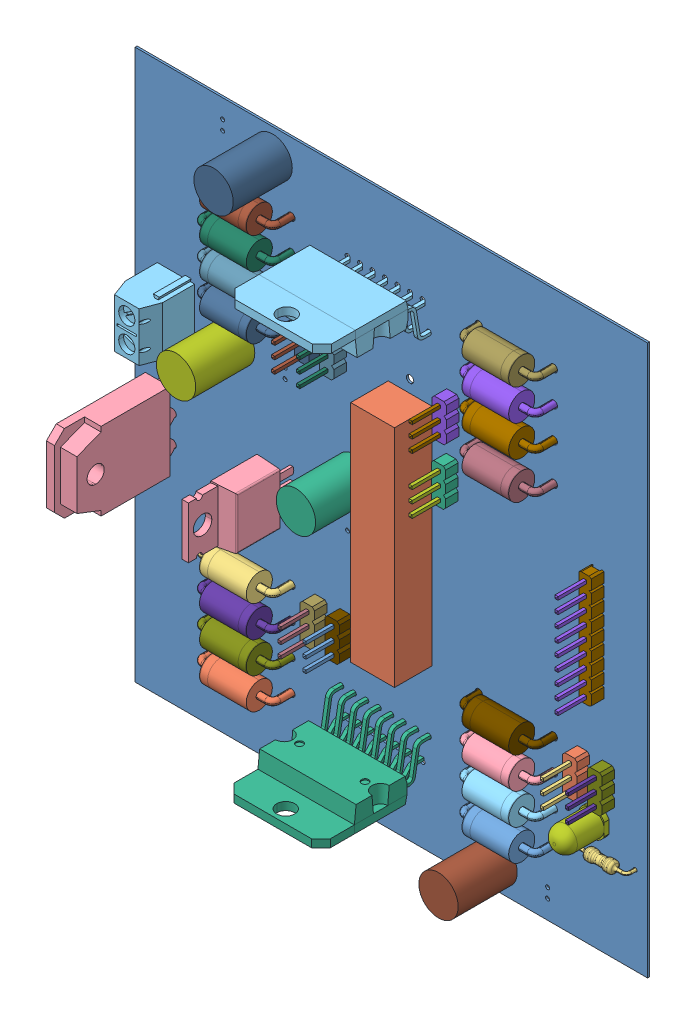
SolidWorks assembly TestServoCircuit, configuration Default. Lengths in mm.
Overall size (104.14 111.76 40.3).
108 component instances, 47 part files, 0 mates.
Components (placement in the parent):
- TestServoCircuit(2)^TestServoCircuit-1: TestServoCircuit(2)^TestServoCircuit [Default] at origin size (104.14 111.76 40.3) (virtual)
  - Board^TestServoCircuit(2)_TestServoCircuit-1: Board^TestServoCircuit(2)_TestServoCircuit [Default] at origin size (104.14 111.76 0.41) (virtual)
    - Open CASCADE STEP translator 6.8 2.1.1^Board_TestServoCircuit(2)_TestServoCircuit-1: Open CASCADE STEP translator 6.8 2.1.1^Board_TestServoCircuit(2)_TestServoCircuit [Default] at (0 0 -0.4115) size (104.14 111.76 0.41) (virtual)
  - R2^TestServoCircuit(2)_TestServoCircuit-1: R2^TestServoCircuit(2)_TestServoCircuit [Default] at origin size (8.89 45.72 7.62) (virtual)
    - 8621058528^R2_TestServoCircuit(2)_TestServoCircuit-1: 8621058528^R2_TestServoCircuit(2)_TestServoCircuit [Default] at (55.88 55.88 0) size (8.89 45.72 7.62) (virtual)
      - Extruded^8621058528_R2_TestServoCircuit(2)_TestServoCircuit-1: Extruded^8621058528_R2_TestServoCircuit(2)_TestServoCircuit [Default] at origin size (8.89 45.72 7.62) (virtual)
  - R1^TestServoCircuit(2)_TestServoCircuit-1: R1^TestServoCircuit(2)_TestServoCircuit [Default] at origin size (10.77 2.31 5.47) (virtual)
    - SW3dPS-RESISTOR,_0.25_W,_0.4_IN_LEAD_PITCH^R1_TestServoCircuit(2)_TestServoCircuit-1: SW3dPS-RESISTOR,_0.25_W,_0.4_IN_LEAD_PITCH^R1_TestServoCircuit(2)_TestServoCircuit [Default] at (101.5999 17.7799 0) x (-1 0 0) z (0 1 0) size (10.77 5.47 2.31) (virtual)
  - Q1^TestServoCircuit(2)_TestServoCircuit-1: Q1^TestServoCircuit(2)_TestServoCircuit [Default] at origin size (5 15.8 40.3) (virtual)
    - TO-3P^Q1_TestServoCircuit(2)_TestServoCircuit-1: TO-3P^Q1_TestServoCircuit(2)_TestServoCircuit [Default] at (5.5881 51.1699 13.563) x (0 1 0) z (1 0 0) size (15.8 40.3 5) (virtual)
  - P1^TestServoCircuit(2)_TestServoCircuit-1: P1^TestServoCircuit(2)_TestServoCircuit [Default] at origin size (7.6 10.6 13) (virtual)
    - User_Library-Terminal-Screw-3A-2way^P1_TestServoCircuit(2)_TestServoCircuit-1: User_Library-Terminal-Screw-3A-2way^P1_TestServoCircuit(2)_TestServoCircuit [Default] at (8.3199 71.1201 0.0127) x (0 -1 0) z (-1 0 0) size (10.6 13 7.6) (virtual)
  - J8^TestServoCircuit(2)_TestServoCircuit-1: J8^TestServoCircuit(2)_TestServoCircuit [Default] at origin size (2.92 7.62 12.19) (virtual)
    - User_Library-PinHeaderX3^J8_TestServoCircuit(2)_TestServoCircuit-1: User_Library-PinHeaderX3^J8_TestServoCircuit(2)_TestServoCircuit [Default] at (64.707 71.12 0.508) x (0 -1 0) z (-1 0 0) size (7.62 12.19 2.92) (virtual)
      - User_Library-PinHeaderX3_PinHeader_Body_1^User_Library-PinHeaderX3_J8_TestServoCircuit(2)_TestServoCircuit-1: User_Library-PinHeaderX3_PinHeader_Body_1^User_Library-PinHeaderX3_J8_TestServoCircuit(2)_TestServoCircuit [Default] at origin size (7.62 2.54 2.92) (virtual)
      - User_Library-PinHeaderX3_PinHeader_Pins_1^User_Library-PinHeaderX3_J8_TestServoCircuit(2)_TestServoCircuit-1: User_Library-PinHeaderX3_PinHeader_Pins_1^User_Library-PinHeaderX3_J8_TestServoCircuit(2)_TestServoCircuit [Default] at origin size (5.72 12.19 0.64) (virtual)
  - J7^TestServoCircuit(2)_TestServoCircuit-1: J7^TestServoCircuit(2)_TestServoCircuit [Default] at origin size (2.92 7.62 12.19) (virtual)
    - User_Library-PinHeaderX3^J7_TestServoCircuit(2)_TestServoCircuit-1: User_Library-PinHeaderX3^J7_TestServoCircuit(2)_TestServoCircuit [Default] at (64.833 77.47 0.508) x (0 1 0) z (1 0 0) size (7.62 12.19 2.92) (virtual)
      - User_Library-PinHeaderX3_PinHeader_Body_1^User_Library-PinHeaderX3_J7_TestServoCircuit(2)_TestServoCircuit-1: User_Library-PinHeaderX3_PinHeader_Body_1^User_Library-PinHeaderX3_J7_TestServoCircuit(2)_TestServoCircuit [Default] at origin size (7.62 2.54 2.92) (virtual)
      - User_Library-PinHeaderX3_PinHeader_Pins_1^User_Library-PinHeaderX3_J7_TestServoCircuit(2)_TestServoCircuit-1: User_Library-PinHeaderX3_PinHeader_Pins_1^User_Library-PinHeaderX3_J7_TestServoCircuit(2)_TestServoCircuit [Default] at origin size (5.72 12.19 0.64) (virtual)
  - J6^TestServoCircuit(2)_TestServoCircuit-1: J6^TestServoCircuit(2)_TestServoCircuit [Default] at origin size (2.92 7.62 12.19) (virtual)
    - User_Library-PinHeaderX3^J6_TestServoCircuit(2)_TestServoCircuit-1: User_Library-PinHeaderX3^J6_TestServoCircuit(2)_TestServoCircuit [Default] at (36.893 77.4446 0.508) x (0 1 0) z (1 0 0) size (7.62 12.19 2.92) (virtual)
      - User_Library-PinHeaderX3_PinHeader_Body_1^User_Library-PinHeaderX3_J6_TestServoCircuit(2)_TestServoCircuit-1: User_Library-PinHeaderX3_PinHeader_Body_1^User_Library-PinHeaderX3_J6_TestServoCircuit(2)_TestServoCircuit [Default] at origin size (7.62 2.54 2.92) (virtual)
      - User_Library-PinHeaderX3_PinHeader_Pins_1^User_Library-PinHeaderX3_J6_TestServoCircuit(2)_TestServoCircuit-1: User_Library-PinHeaderX3_PinHeader_Pins_1^User_Library-PinHeaderX3_J6_TestServoCircuit(2)_TestServoCircuit [Default] at origin size (5.72 12.19 0.64) (virtual)
  - J5^TestServoCircuit(2)_TestServoCircuit-1: J5^TestServoCircuit(2)_TestServoCircuit [Default] at origin size (2.92 7.62 12.19) (virtual)
    - User_Library-PinHeaderX3^J5_TestServoCircuit(2)_TestServoCircuit-1: User_Library-PinHeaderX3^J5_TestServoCircuit(2)_TestServoCircuit [Default] at (38.037 33.02 0.508) x (0 -1 0) z (-1 0 0) size (7.62 12.19 2.92) (virtual)
      - User_Library-PinHeaderX3_PinHeader_Body_1^User_Library-PinHeaderX3_J5_TestServoCircuit(2)_TestServoCircuit-1: User_Library-PinHeaderX3_PinHeader_Body_1^User_Library-PinHeaderX3_J5_TestServoCircuit(2)_TestServoCircuit [Default] at origin size (7.62 2.54 2.92) (virtual)
      - User_Library-PinHeaderX3_PinHeader_Pins_1^User_Library-PinHeaderX3_J5_TestServoCircuit(2)_TestServoCircuit-1: User_Library-PinHeaderX3_PinHeader_Pins_1^User_Library-PinHeaderX3_J5_TestServoCircuit(2)_TestServoCircuit [Default] at origin size (5.72 12.19 0.64) (virtual)
  - J4^TestServoCircuit(2)_TestServoCircuit-1: J4^TestServoCircuit(2)_TestServoCircuit [Default] at origin size (2.92 7.62 12.19) (virtual)
    - User_Library-PinHeaderX3^J4_TestServoCircuit(2)_TestServoCircuit-1: User_Library-PinHeaderX3^J4_TestServoCircuit(2)_TestServoCircuit [Default] at (41.973 77.4446 0.508) x (0 1 0) z (1 0 0) size (7.62 12.19 2.92) (virtual)
      - User_Library-PinHeaderX3_PinHeader_Body_1^User_Library-PinHeaderX3_J4_TestServoCircuit(2)_TestServoCircuit-1: User_Library-PinHeaderX3_PinHeader_Body_1^User_Library-PinHeaderX3_J4_TestServoCircuit(2)_TestServoCircuit [Default] at origin size (7.62 2.54 2.92) (virtual)
      - User_Library-PinHeaderX3_PinHeader_Pins_1^User_Library-PinHeaderX3_J4_TestServoCircuit(2)_TestServoCircuit-1: User_Library-PinHeaderX3_PinHeader_Pins_1^User_Library-PinHeaderX3_J4_TestServoCircuit(2)_TestServoCircuit [Default] at origin size (5.72 12.19 0.64) (virtual)
  - J3^TestServoCircuit(2)_TestServoCircuit-1: J3^TestServoCircuit(2)_TestServoCircuit [Default] at origin size (2.92 7.62 12.19) (virtual)
    - User_Library-PinHeaderX3^J3_TestServoCircuit(2)_TestServoCircuit-1: User_Library-PinHeaderX3^J3_TestServoCircuit(2)_TestServoCircuit [Default] at (96.457 33.02 0.508) x (0 -1 0) z (-1 0 0) size (7.62 12.19 2.92) (virtual)
      - User_Library-PinHeaderX3_PinHeader_Body_1^User_Library-PinHeaderX3_J3_TestServoCircuit(2)_TestServoCircuit-1: User_Library-PinHeaderX3_PinHeader_Body_1^User_Library-PinHeaderX3_J3_TestServoCircuit(2)_TestServoCircuit [Default] at origin size (7.62 2.54 2.92) (virtual)
      - User_Library-PinHeaderX3_PinHeader_Pins_1^User_Library-PinHeaderX3_J3_TestServoCircuit(2)_TestServoCircuit-1: User_Library-PinHeaderX3_PinHeader_Pins_1^User_Library-PinHeaderX3_J3_TestServoCircuit(2)_TestServoCircuit [Default] at origin size (5.72 12.19 0.64) (virtual)
  - J2^TestServoCircuit(2)_TestServoCircuit-1: J2^TestServoCircuit(2)_TestServoCircuit [Default] at origin size (2.92 7.62 12.19) (virtual)
    - User_Library-PinHeaderX3^J2_TestServoCircuit(2)_TestServoCircuit-1: User_Library-PinHeaderX3^J2_TestServoCircuit(2)_TestServoCircuit [Default] at (43.117 33.02 0.508) x (0 -1 0) z (-1 0 0) size (7.62 12.19 2.92) (virtual)
      - User_Library-PinHeaderX3_PinHeader_Body_1^User_Library-PinHeaderX3_J2_TestServoCircuit(2)_TestServoCircuit-1: User_Library-PinHeaderX3_PinHeader_Body_1^User_Library-PinHeaderX3_J2_TestServoCircuit(2)_TestServoCircuit [Default] at origin size (7.62 2.54 2.92) (virtual)
      - User_Library-PinHeaderX3_PinHeader_Pins_1^User_Library-PinHeaderX3_J2_TestServoCircuit(2)_TestServoCircuit-1: User_Library-PinHeaderX3_PinHeader_Pins_1^User_Library-PinHeaderX3_J2_TestServoCircuit(2)_TestServoCircuit [Default] at origin size (5.72 12.19 0.64) (virtual)
  - J1^TestServoCircuit(2)_TestServoCircuit-1: J1^TestServoCircuit(2)_TestServoCircuit [Default] at origin size (2.92 7.62 12.19) (virtual)
    - User_Library-PinHeaderX3^J1_TestServoCircuit(2)_TestServoCircuit-1: User_Library-PinHeaderX3^J1_TestServoCircuit(2)_TestServoCircuit [Default] at (91.377 33.02 0.508) x (0 -1 0) z (-1 0 0) size (7.62 12.19 2.92) (virtual)
      - User_Library-PinHeaderX3_PinHeader_Body_1^User_Library-PinHeaderX3_J1_TestServoCircuit(2)_TestServoCircuit-1: User_Library-PinHeaderX3_PinHeader_Body_1^User_Library-PinHeaderX3_J1_TestServoCircuit(2)_TestServoCircuit [Default] at origin size (7.62 2.54 2.92) (virtual)
      - User_Library-PinHeaderX3_PinHeader_Pins_1^User_Library-PinHeaderX3_J1_TestServoCircuit(2)_TestServoCircuit-1: User_Library-PinHeaderX3_PinHeader_Pins_1^User_Library-PinHeaderX3_J1_TestServoCircuit(2)_TestServoCircuit [Default] at origin size (5.72 12.19 0.64) (virtual)
  - IC3^TestServoCircuit(2)_TestServoCircuit-1: IC3^TestServoCircuit(2)_TestServoCircuit [Default] at origin size (4.69 11.21 29.33) (virtual)
    - SW3dPS-TO220AB^IC3_TestServoCircuit(2)_TestServoCircuit-1: SW3dPS-TO220AB^IC3_TestServoCircuit(2)_TestServoCircuit [Default] at (31.8806 48.304 -10.16) x (0 1 0) z (0 0 1) size (11.21 4.69 29.33) (virtual)
  - IC2^TestServoCircuit(2)_TestServoCircuit-1: IC2^TestServoCircuit(2)_TestServoCircuit [Default] at origin size (19.6 9.07 24.92) (virtual)
    - User_Library-MULTIWAT_T15^IC2_TestServoCircuit(2)_TestServoCircuit-1: User_Library-MULTIWAT_T15^IC2_TestServoCircuit(2)_TestServoCircuit [Default] at (41.1018 100.2586 5.2392) x (0 -1 0) z (-1 0 0) size (9.07 24.92 19.6) (virtual)
  - IC1^TestServoCircuit(2)_TestServoCircuit-1: IC1^TestServoCircuit(2)_TestServoCircuit [Default] at origin size (19.6 9.07 24.92) (virtual)
    - User_Library-MULTIWAT_T15^IC1_TestServoCircuit(2)_TestServoCircuit-1: User_Library-MULTIWAT_T15^IC1_TestServoCircuit(2)_TestServoCircuit [Default] at (60.4983 11.5014 5.2392) x (0 1 0) z (1 0 0) size (9.07 24.92 19.6) (virtual)
  - D17^TestServoCircuit(2)_TestServoCircuit-1: D17^TestServoCircuit(2)_TestServoCircuit [Default] at origin size (5.3 5.6 14.3) (virtual)
    - LED_5mm_Green^D17_TestServoCircuit(2)_TestServoCircuit-1: LED_5mm_Green^D17_TestServoCircuit(2)_TestServoCircuit [Default] at (93.9801 22.8601 -3.5) x (1 0 0) z (0 -1 0) size (5.3 14.3 5.6) (virtual)
  - D16^TestServoCircuit(2)_TestServoCircuit-1: D16^TestServoCircuit(2)_TestServoCircuit [Default] at origin size (16.3 5.3 8.65) (virtual)
    - User_Library-BYW98^D16_TestServoCircuit(2)_TestServoCircuit-1: User_Library-BYW98^D16_TestServoCircuit(2)_TestServoCircuit [Default] at (77.47 91.4399 3.65) x (-1 0 0) z (0 1 0) size (16.3 8.65 5.3) (virtual)
  - D15^TestServoCircuit(2)_TestServoCircuit-1: D15^TestServoCircuit(2)_TestServoCircuit [Default] at origin size (16.3 5.3 8.65) (virtual)
    - User_Library-BYW98^D15_TestServoCircuit(2)_TestServoCircuit-1: User_Library-BYW98^D15_TestServoCircuit(2)_TestServoCircuit [Default] at (77.47 85.0899 3.65) x (-1 0 0) z (0 1 0) size (16.3 8.65 5.3) (virtual)
  - D14^TestServoCircuit(2)_TestServoCircuit-1: D14^TestServoCircuit(2)_TestServoCircuit [Default] at origin size (16.3 5.3 8.65) (virtual)
    - User_Library-BYW98^D14_TestServoCircuit(2)_TestServoCircuit-1: User_Library-BYW98^D14_TestServoCircuit(2)_TestServoCircuit [Default] at (24.13 78.7401 3.65) x (1 0 0) z (0 -1 0) size (16.3 8.65 5.3) (virtual)
  - D13^TestServoCircuit(2)_TestServoCircuit-1: D13^TestServoCircuit(2)_TestServoCircuit [Default] at origin size (16.3 5.3 8.65) (virtual)
    - User_Library-BYW98^D13_TestServoCircuit(2)_TestServoCircuit-1: User_Library-BYW98^D13_TestServoCircuit(2)_TestServoCircuit [Default] at (24.13 97.7901 3.65) x (1 0 0) z (0 -1 0) size (16.3 8.65 5.3) (virtual)
  - D12^TestServoCircuit(2)_TestServoCircuit-1: D12^TestServoCircuit(2)_TestServoCircuit [Default] at origin size (16.3 5.3 8.65) (virtual)
    - User_Library-BYW98^D12_TestServoCircuit(2)_TestServoCircuit-1: User_Library-BYW98^D12_TestServoCircuit(2)_TestServoCircuit [Default] at (77.4701 97.7901 3.65) x (1 0 0) z (0 -1 0) size (16.3 8.65 5.3) (virtual)
  - D11^TestServoCircuit(2)_TestServoCircuit-1: D11^TestServoCircuit(2)_TestServoCircuit [Default] at origin size (16.3 5.3 8.65) (virtual)
    - User_Library-BYW98^D11_TestServoCircuit(2)_TestServoCircuit-1: User_Library-BYW98^D11_TestServoCircuit(2)_TestServoCircuit [Default] at (77.4701 77.4701 3.65) x (1 0 0) z (0 -1 0) size (16.3 8.65 5.3) (virtual)
  - D10^TestServoCircuit(2)_TestServoCircuit-1: D10^TestServoCircuit(2)_TestServoCircuit [Default] at origin size (16.3 5.3 8.65) (virtual)
    - User_Library-BYW98^D10_TestServoCircuit(2)_TestServoCircuit-1: User_Library-BYW98^D10_TestServoCircuit(2)_TestServoCircuit [Default] at (24.1299 85.0899 3.65) x (-1 0 0) z (0 1 0) size (16.3 8.65 5.3) (virtual)
  - D9^TestServoCircuit(2)_TestServoCircuit-1: D9^TestServoCircuit(2)_TestServoCircuit [Default] at origin size (16.3 5.3 8.65) (virtual)
    - User_Library-BYW98^D9_TestServoCircuit(2)_TestServoCircuit-1: User_Library-BYW98^D9_TestServoCircuit(2)_TestServoCircuit [Default] at (24.1299 91.4399 3.65) x (-1 0 0) z (0 1 0) size (16.3 8.65 5.3) (virtual)
  - D8^TestServoCircuit(2)_TestServoCircuit-1: D8^TestServoCircuit(2)_TestServoCircuit [Default] at origin size (16.3 5.3 8.65) (virtual)
    - User_Library-BYW98^D8_TestServoCircuit(2)_TestServoCircuit-1: User_Library-BYW98^D8_TestServoCircuit(2)_TestServoCircuit [Default] at (24.13 20.3201 3.65) x (1 0 0) z (0 -1 0) size (16.3 8.65 5.3) (virtual)
  - D7^TestServoCircuit(2)_TestServoCircuit-1: D7^TestServoCircuit(2)_TestServoCircuit [Default] at origin size (16.3 5.3 8.65) (virtual)
    - User_Library-BYW98^D7_TestServoCircuit(2)_TestServoCircuit-1: User_Library-BYW98^D7_TestServoCircuit(2)_TestServoCircuit [Default] at (24.13 26.6701 3.65) x (1 0 0) z (0 -1 0) size (16.3 8.65 5.3) (virtual)
  - D6^TestServoCircuit(2)_TestServoCircuit-1: D6^TestServoCircuit(2)_TestServoCircuit [Default] at origin size (16.3 5.3 8.65) (virtual)
    - User_Library-BYW98^D6_TestServoCircuit(2)_TestServoCircuit-1: User_Library-BYW98^D6_TestServoCircuit(2)_TestServoCircuit [Default] at (77.47 33.0199 3.65) x (-1 0 0) z (0 1 0) size (16.3 8.65 5.3) (virtual)
  - D5^TestServoCircuit(2)_TestServoCircuit-1: D5^TestServoCircuit(2)_TestServoCircuit [Default] at origin size (16.3 5.3 8.65) (virtual)
    - User_Library-BYW98^D5_TestServoCircuit(2)_TestServoCircuit-1: User_Library-BYW98^D5_TestServoCircuit(2)_TestServoCircuit [Default] at (77.47 13.9699 3.65) x (-1 0 0) z (0 1 0) size (16.3 8.65 5.3) (virtual)
  - D4^TestServoCircuit(2)_TestServoCircuit-1: D4^TestServoCircuit(2)_TestServoCircuit [Default] at origin size (16.3 5.3 8.65) (virtual)
    - User_Library-BYW98^D4_TestServoCircuit(2)_TestServoCircuit-1: User_Library-BYW98^D4_TestServoCircuit(2)_TestServoCircuit [Default] at (24.1299 13.9699 3.65) x (-1 0 0) z (0 1 0) size (16.3 8.65 5.3) (virtual)
  - D3^TestServoCircuit(2)_TestServoCircuit-1: D3^TestServoCircuit(2)_TestServoCircuit [Default] at origin size (16.3 5.3 8.65) (virtual)
    - User_Library-BYW98^D3_TestServoCircuit(2)_TestServoCircuit-1: User_Library-BYW98^D3_TestServoCircuit(2)_TestServoCircuit [Default] at (24.1299 33.0199 3.65) x (-1 0 0) z (0 1 0) size (16.3 8.65 5.3) (virtual)
  - D2^TestServoCircuit(2)_TestServoCircuit-1: D2^TestServoCircuit(2)_TestServoCircuit [Default] at origin size (16.3 5.3 8.65) (virtual)
    - User_Library-BYW98^D2_TestServoCircuit(2)_TestServoCircuit-1: User_Library-BYW98^D2_TestServoCircuit(2)_TestServoCircuit [Default] at (77.4701 26.6701 3.65) x (1 0 0) z (0 -1 0) size (16.3 8.65 5.3) (virtual)
  - D1^TestServoCircuit(2)_TestServoCircuit-1: D1^TestServoCircuit(2)_TestServoCircuit [Default] at origin size (16.3 5.3 8.65) (virtual)
    - User_Library-BYW98^D1_TestServoCircuit(2)_TestServoCircuit-1: User_Library-BYW98^D1_TestServoCircuit(2)_TestServoCircuit [Default] at (77.4701 20.3201 3.65) x (1 0 0) z (0 -1 0) size (16.3 8.65 5.3) (virtual)
  - C8^TestServoCircuit(2)_TestServoCircuit-1: C8^TestServoCircuit(2)_TestServoCircuit [Default] at origin size (8 8 12) (virtual)
    - 8621055088^C8_TestServoCircuit(2)_TestServoCircuit-1: 8621055088^C8_TestServoCircuit(2)_TestServoCircuit [Default] at (44.68 58.42 0) x (1 0 0) z (0 0 1) size (8 8 12) (virtual)
      - Cylinder^8621055088_C8_TestServoCircuit(2)_TestServoCircuit-1: Cylinder^8621055088_C8_TestServoCircuit(2)_TestServoCircuit [Default] at origin size (8 8 12) (virtual)
  - C6^TestServoCircuit(2)_TestServoCircuit-1: C6^TestServoCircuit(2)_TestServoCircuit [Default] at origin size (8 8 12) (virtual)
    - 8621054848^C6_TestServoCircuit(2)_TestServoCircuit-1: 8621054848^C6_TestServoCircuit(2)_TestServoCircuit [Default] at (20.32 70.08 0) x (0 1 0) z (0 0 1) size (8 8 12) (virtual)
      - Cylinder-0^8621054848_C6_TestServoCircuit(2)_TestServoCircuit-1: Cylinder-0^8621054848_C6_TestServoCircuit(2)_TestServoCircuit [Default] at origin size (8 8 12) (virtual)
  - C5^TestServoCircuit(2)_TestServoCircuit-1: C5^TestServoCircuit(2)_TestServoCircuit [Default] at origin size (2.54 22.86 11.54) (virtual)
    - 61300911121^C5_TestServoCircuit(2)_TestServoCircuit-1: 61300911121^C5_TestServoCircuit(2)_TestServoCircuit [Default] at (93.9799 55.8801 1.27) x (0 1 0) z (1 0 0) size (22.86 11.54 2.54) (virtual)
      - 6130xx11121_PIN^61300911121_C5_TestServoCircuit(2)_TestServoCircuit-1: 6130xx11121_PIN^61300911121_C5_TestServoCircuit(2)_TestServoCircuit [Default] at (-10.16 1.5 0) x (1 0 0) z (0 -1 0) size (0.64 0.64 11.54) (virtual)
      - 6130xx11121_PIN^61300911121_C5_TestServoCircuit(2)_TestServoCircuit-2: 6130xx11121_PIN^61300911121_C5_TestServoCircuit(2)_TestServoCircuit [Default] at (-7.62 1.5 0) x (1 0 0) z (0 -1 0) size (0.64 0.64 11.54) (virtual)
      - 6130xx11121_PIN^61300911121_C5_TestServoCircuit(2)_TestServoCircuit-3: 6130xx11121_PIN^61300911121_C5_TestServoCircuit(2)_TestServoCircuit [Default] at (-5.08 1.5 0) x (1 0 0) z (0 -1 0) size (0.64 0.64 11.54) (virtual)
      - 6130xx11121_PIN^61300911121_C5_TestServoCircuit(2)_TestServoCircuit-4: 6130xx11121_PIN^61300911121_C5_TestServoCircuit(2)_TestServoCircuit [Default] at (-2.54 1.5 0) x (1 0 0) z (0 -1 0) size (0.64 0.64 11.54) (virtual)
      - 6130xx11121_PIN^61300911121_C5_TestServoCircuit(2)_TestServoCircuit-5: 6130xx11121_PIN^61300911121_C5_TestServoCircuit(2)_TestServoCircuit [Default] at (0 1.5 0) x (1 0 0) z (0 -1 0) size (0.64 0.64 11.54) (virtual)
      - 6130xx11121_PIN^61300911121_C5_TestServoCircuit(2)_TestServoCircuit-6: 6130xx11121_PIN^61300911121_C5_TestServoCircuit(2)_TestServoCircuit [Default] at (2.54 1.5 0) x (1 0 0) z (0 -1 0) size (0.64 0.64 11.54) (virtual)
      - 6130xx11121_PIN^61300911121_C5_TestServoCircuit(2)_TestServoCircuit-7: 6130xx11121_PIN^61300911121_C5_TestServoCircuit(2)_TestServoCircuit [Default] at (5.08 1.5 0) x (1 0 0) z (0 -1 0) size (0.64 0.64 11.54) (virtual)
      - 6130xx11121_PIN^61300911121_C5_TestServoCircuit(2)_TestServoCircuit-8: 6130xx11121_PIN^61300911121_C5_TestServoCircuit(2)_TestServoCircuit [Default] at (7.62 1.5 0) x (1 0 0) z (0 -1 0) size (0.64 0.64 11.54) (virtual)
      - 6130xx11121_PIN^61300911121_C5_TestServoCircuit(2)_TestServoCircuit-9: 6130xx11121_PIN^61300911121_C5_TestServoCircuit(2)_TestServoCircuit [Default] at (10.16 1.5 0) x (1 0 0) z (0 -1 0) size (0.64 0.64 11.54) (virtual)
      - 61300911121-1^61300911121_C5_TestServoCircuit(2)_TestServoCircuit-1: 61300911121-1^61300911121_C5_TestServoCircuit(2)_TestServoCircuit [Default] at origin size (22.86 2.54 2.54) (virtual)
  - C3^TestServoCircuit(2)_TestServoCircuit-1: C3^TestServoCircuit(2)_TestServoCircuit [Default] at origin size (8 8 12) (virtual)
    - 8621054448^C3_TestServoCircuit(2)_TestServoCircuit-1: 8621054448^C3_TestServoCircuit(2)_TestServoCircuit [Default] at (27.94 106.45 0) x (0 -1 0) z (0 0 1) size (8 8 12) (virtual)
      - Cylinder-2^8621054448_C3_TestServoCircuit(2)_TestServoCircuit-1: Cylinder-2^8621054448_C3_TestServoCircuit(2)_TestServoCircuit [Default] at origin size (8 8 12) (virtual)
  - C1^TestServoCircuit(2)_TestServoCircuit-1: C1^TestServoCircuit(2)_TestServoCircuit [Default] at origin size (8 8 12) (virtual)
    - 8621054848^C1_TestServoCircuit(2)_TestServoCircuit-1: 8621054848^C1_TestServoCircuit(2)_TestServoCircuit [Default] at (73.66 5.31 0) x (0 1 0) z (0 0 1) size (8 8 12) (virtual)
      - Cylinder-0^8621054848_C1_TestServoCircuit(2)_TestServoCircuit-1: Cylinder-0^8621054848_C1_TestServoCircuit(2)_TestServoCircuit [Default] at origin size (8 8 12) (virtual)
